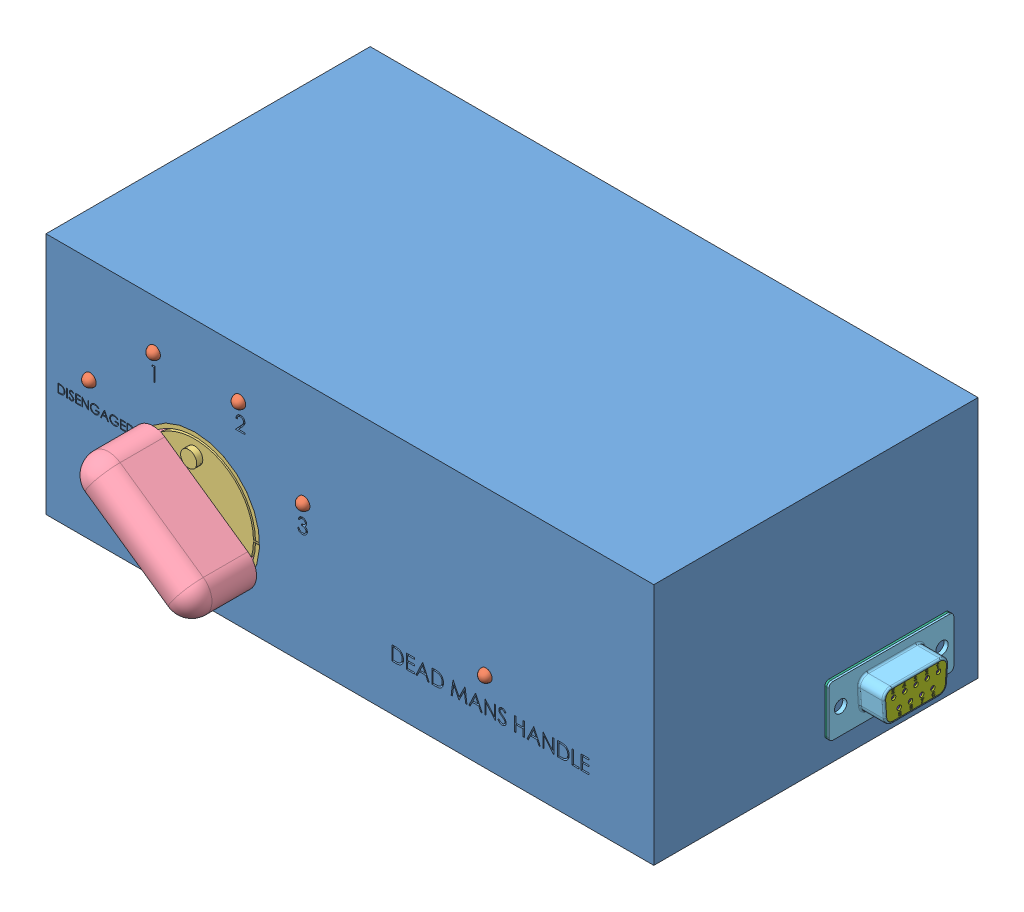
SolidWorks assembly Control Panel Assembly v2, configuration Default. Lengths in mm.
Overall size (157.2 67.15 96.03).
21 component instances, 8 part files, 8 mates.
Components (placement in the parent):
- Control Panel box v2-2: Control Panel box v2 [Default] at (87.3701 96.6433 197.0014) x (-1 0 0) z (0 -1 0) size (150 80 60)
- LED_3MM-1: LED_3MM [Predeterminado] at (-51.7427 70.9064 193.0014) x (-0.923728 -0.383049 0) z (-0.383049 0.923728 0) size (3.37 9.49 3.74)
- LED_3MM-2: LED_3MM [Predeterminado] at (-35.8873 84.7189 193.0014) x (-0.923728 -0.383049 0) z (-0.383049 0.923728 0) size (3.37 9.49 3.74)
- LED_3MM-3: LED_3MM [Predeterminado] at (-14.8593 84.7189 193.0014) x (-0.923728 -0.383049 0) z (-0.383049 0.923728 0) size (3.37 9.49 3.74)
- LED_3MM-4: LED_3MM [Predeterminado] at (0.9961 70.9064 193.0014) x (-0.923728 -0.383049 0) z (-0.383049 0.923728 0) size (3.37 9.49 3.74)
- LED_3MM-5: LED_3MM [Predeterminado] at (45.9519 56.6433 193.0014) x (-0.923728 -0.383049 0) z (-0.383049 0.923728 0) size (3.37 9.49 3.74)
- Pieza 1_1-1: Pieza 1_1 [Predeterminado] at (-25.9283 56.6433 211.0014) size (32 32 32.5)
- Cap1-1: Cap1 [Predeterminado] at (-25.9283 56.6433 192.0014) x (0.571757 0.820423 0) z (0.820423 -0.571757 0) size (39 21.03 39)
- D-tupe 9 pin female-1: D-tupe 9 pin female [Default] at (66.3219 31.1642 153.2263) x (0 0 -1) z (1 0 0) size (30.84 12.55 15.35)
  - D-type 2-1: D-type 2 [Default] at (13.8361 17.4152 21.5482) size (30.84 12.55 7.3)
  - D-type 1-1: D-type 1 [Default] at (13.8361 17.4152 21.5482) x (-1 0 0) z (0 0 -1) size (30.84 12.55 4.4)
  - D-type 3-1: D-type 3 [Default] at (13.8361 17.4152 17.6482) size (16.3 8.2 12.45)
  - D-type pin female-1: D-type pin female [Default] at (19.3761 18.8352 27.7482) x (-1 0 0) z (0 0 -1) size (1.6 1.6 14.86)
  - D-type pin female-2: D-type pin female [Default] at (16.6061 18.8352 27.7482) x (-1 0 0) z (0 0 -1) size (1.6 1.6 14.86)
  - D-type pin female-3: D-type pin female [Default] at (13.8361 18.8352 27.7482) x (-1 0 0) z (0 0 -1) size (1.6 1.6 14.86)
  - D-type pin female-4: D-type pin female [Default] at (11.0661 18.8352 27.7482) x (-1 0 0) z (0 0 -1) size (1.6 1.6 14.86)
  - D-type pin female-5: D-type pin female [Default] at (8.2961 18.8352 27.7482) x (-1 0 0) z (0 0 -1) size (1.6 1.6 14.86)
  - D-type pin female-6: D-type pin female [Default] at (9.6855 15.9952 27.7482) x (1 0 0) z (0 0 -1) size (1.6 1.6 14.86)
  - D-type pin female-7: D-type pin female [Default] at (12.4555 15.9952 27.7482) x (1 0 0) z (0 0 -1) size (1.6 1.6 14.86)
  - D-type pin female-8: D-type pin female [Default] at (17.9955 15.9952 27.7482) x (1 0 0) z (0 0 -1) size (1.6 1.6 14.86)
  - D-type pin female-9: D-type pin female [Default] at (15.2255 15.9952 27.7482) x (1 0 0) z (0 0 -1) size (1.6 1.6 14.86)
Mates (geometry in assembly coordinates):
- Coincident1: coincident aligned: circle of Control Panel box v2-2; circle of LED_3MM-1
- Coincident2: coincident aligned: circle of Control Panel box v2-2; circle of LED_3MM-2
- Coincident3: coincident aligned: circle of Control Panel box v2-2; circle of LED_3MM-3
- Coincident4: coincident aligned: circle of Control Panel box v2-2; circle of LED_3MM-4
- Coincident5: coincident aligned: circle of Control Panel box v2-2; circle of LED_3MM-5
- Coincident6: coincident aligned: circle of Control Panel box v2-2; circle of Pieza 1-1
- Coincident7: coincident aligned: circle of Cap-1; circle of Pieza 1-1
- Coincident8: coincident anti-aligned: plane of Control Panel box v2-2 through (87.3701 36.6433 197.0014) normal (1 0 0); plane of D-tupe 9 pin female-1/D-type 1-1 through (87.3701 53.8544 153.8102) normal (-1 0 0)
